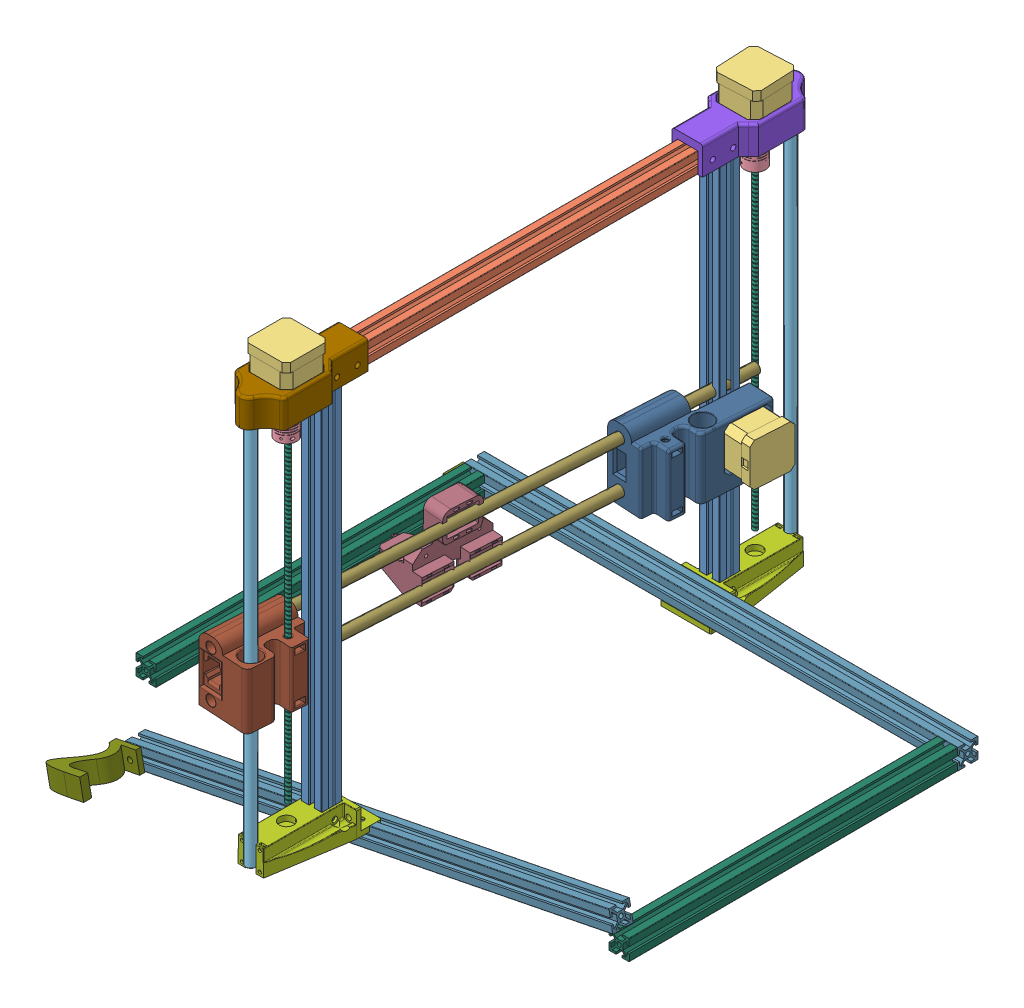
SolidWorks assembly sE1X Complete Assembly, configuration Default. Lengths in mm.
Overall size (525.97 503.54 556.73).
27 component instances, 16 part files, 45 mates.
Components (placement in the parent):
- sE1X 398mm Z axis 2020 extrusion-1: sE1X 398mm Z axis 2020 extrusion [Default] at origin size (20 398 20)
- sE1X 398mm Z axis 2020 extrusion-3: sE1X 398mm Z axis 2020 extrusion [Default] at (0 0 391.25) size (20 398 20)
- 370mm X axis 2020 extrusion-4: 370mm X axis 2020 extrusion [Default] at (0 410 -38.75) x (-1 0 0) z (0 1 0) size (20 371.25 20)
- nema17-1: nema17 [Défaut] at (0.3968 404.3307 426.15) x (1 0 0) z (0 1 0) size (42 42 71)
- nema17-2: nema17 [Défaut] at (-0.1 404.8 -35) x (0.998806 0 -0.048861) z (0 1 0) size (42 42 71)
- 5mm coupler-1: 5mm coupler [Valor predeterminado] at (-0.1 383.0903 -35) x (0 -1 0) z (-0.000286 0 1) size (25 20.35 21.4)
- 5mm coupler-2: 5mm coupler [Valor predeterminado] at (0.3968 382.7752 426.15) x (0 1 0) z (0.001793 0 0.999998) size (25 20.35 21.4)
- sE1X 398mm 10mm smooth rod-1: sE1X 398mm 10mm smooth rod [Default] at (0.2968 22.246 461.05) x (-0.139408 0 0.990235) z (0 1 0) size (10 10 390)
- sE1X 398mm 10mm smooth rod-2: sE1X 398mm 10mm smooth rod [Default] at (-0.1 409.8 -70) x (0.998806 0 -0.048861) z (0 -1 0) size (10 10 390)
- 5mm threaded rod-1: 5mm threaded rod [Default] at (2.3166 59.2307 426.4289) x (0.999998 0 -0.001793) z (0.001793 0 0.999998) size (5.07 324.29 5)
- 5mm threaded rod-2: 5mm threaded rod [Default] at (-0.1 59.7 -35) x (0.998806 0 -0.048861) z (0.048861 0 0.998806) size (5.07 324.29 5)
- sE1X Z Axis bottom bracket-2: sE1X Z Axis bottom bracket [Default] at (-0.1 29.25 33.6) x (-1 0 0) z (0 0 -1) size (50 25 103.66)
- sE1X Z Axis top motor bracket(mirrored)-1: sE1X Z Axis top motor bracket(mirrored) [Mirrored] at (-0.2968 399.8 96.45) size (50 27.84 222.86)
- sE1X Z Axis top motor bracket-3: sE1X Z Axis top motor bracket [Default] at (0.2968 399.8 426.05) size (50 27.84 111.43)
- sE1X X Axis Motor end-1: sE1X X Axis Motor end [Default] at (12.2933 178.2909 40.7975) x (0.058241 0 -0.998303) z (0.998303 0 0.058241) size (110 70.43 50)
- sE1X X idler end-1: sE1X X idler end [Default] at (-35.9747 178.2909 438.8999) x (0.058241 0 -0.998303) z (0.998303 0 0.058241) size (70 65 50)
- sE1X 465mm 10mm smooth rod-3: sE1X 465mm 10mm smooth rod [Default] at (3.9817 155.7909 -31.3582) x (0.998303 0 0.058241) z (-0.058241 0 0.998303) size (10 10 465)
- sE1X 465mm 10mm smooth rod-4: sE1X 465mm 10mm smooth rod [Default] at (4.015 200.7909 -31.9301) x (0.998303 0 0.058241) z (-0.058241 0 0.998303) size (10 10 465)
- SE1X 10mm carriage(BOWDEN)-1: SE1X 10mm carriage(BOWDEN) [10mm config] at (-21.3067 183.1903 239.5265) x (-0.058241 0 0.998303) z (-0.019423 -0.999811 -0.001133) size (75 52.26 71.73)
- nema17-3: nema17 [Défaut] at (17.6074 178.2909 9.8044) x (0.058241 0 -0.998303) z (0.998303 0 0.058241) size (42 42 71)
- sE1X 485mm Z axis 2020 extrusion-1: sE1X 485mm Z axis 2020 extrusion [Default] at (198.7408 46.1901 359.3185) x (0 0 -1) z (-0.195264 0.980751 0) size (20 485 20)
- sE1X 485mm Z axis 2020 extrusion-2: sE1X 485mm Z axis 2020 extrusion [Default] at (202.5107 31.65 23.5) x (0 1 0) z (0 0 1) size (20 485 20)
- 320mm X axis 2020 extrusion-1: 320mm X axis 2020 extrusion [Default] at (-207.4893 31.65 -63.68) x (-1 0 0) z (0 1 0) size (20 322.82 20)
- 320mm X axis 2020 extrusion-2: 320mm X axis 2020 extrusion [Default] at (257.5107 30.3656 453.4889) x (-1 0 0) z (0 -0.999995 -0.003058) size (20 322.82 20)
- Printer Supports -sE1X-1: Printer Supports -sE1X [Default] at (-228.9197 -7.5494 33) x (0 -1 0) z (1 0 0) size (55.14 20 44.55)
- Printer Supports -sE1X-2: Printer Supports -sE1X [Default] at (-214.2758 -26.3535 398.5179) x (0 0 1) z (0.980751 0.195264 0) size (55.14 20 44.55)
- sE1X Z Axis bottom bracket-3: sE1X Z Axis bottom bracket [Default] at (0.2968 29.5 357.45) size (50 25 103.66)
Mates (geometry in assembly coordinates):
- Concentric5: concentric anti-aligned: cylinder of nema17-2 through (-0.1 380.8 -35) axis (0 1 0) radius 2.5; cylinder of 5mm coupler-1 through (-0.1 370.5903 -35) axis (0 -1 0) radius 2.5
- Concentric7: concentric aligned: cylinder of nema17-1 through (0.3968 380.3307 425.9) axis (0 1 0) radius 2.5; cylinder of 5mm coupler-2 through (0.3968 395.2752 425.9) axis (0 1 0) radius 2.5
- Coincident38: coincident anti-aligned: plane of nema17-2 through (-0.1 380.8 -35) normal (0 -1 0); plane of 5mm threaded rod-2 through (-0.1 380.8 -35) normal (0 1 0)
- Concentric16: concentric aligned: cylinder of 5mm coupler-1 through (-0.1 370.5903 -35) axis (0 -1 0) radius 2.5; cylinder of 5mm threaded rod-2 through (-0.1 380.8 -35) axis (0 -1 0) radius 2.5
- Coincident39: coincident anti-aligned: plane of nema17-1 through (0.3968 380.3307 425.9) normal (0 -1 0); plane of 5mm threaded rod-1 through (2.3166 380.3307 426.1789) normal (0 1 0)
- Coincident64: coincident aligned: plane of sE1X 398mm Z axis 2020 extrusion-1 through (10 22 9.5) normal (1 0 0); plane of 370mm X axis 2020 extrusion-4 through (10 400.5 9.75) normal (1 0 0)
- Coincident65: coincident aligned: plane of sE1X 398mm Z axis 2020 extrusion-1 through (9.5 420 -9.5) normal (0 1 0); plane of 370mm X axis 2020 extrusion-4 through (9.5 420 9.75) normal (0 1 0)
- Coincident71: coincident anti-aligned: plane of sE1X 398mm Z axis 2020 extrusion-3 through (-3 22 381) normal (0 0 -1); plane of 370mm X axis 2020 extrusion-4 through (-9.5 400.5 381) normal (0 0 1)
- Coincident72: coincident anti-aligned: plane of sE1X 398mm Z axis 2020 extrusion-1 through (-9.5 22 10) normal (0 0 1); plane of 370mm X axis 2020 extrusion-4 through (-9.5 400.5 9.75) normal (0 0 -1)
- Coincident76: coincident anti-aligned: line of sE1X 398mm Z axis 2020 extrusion-1 through (3 22 10) axis (1 0 0); line of sE1X Z Axis bottom bracket-2 through (9.75 22 10) axis (-1 0 0)
- Coincident77: coincident anti-aligned: plane of sE1X 398mm Z axis 2020 extrusion-1 through (10 22 9.5) normal (1 0 0); plane of sE1X Z Axis bottom bracket-2 through (10 21.75 10) normal (-1 0 0)
- Coincident89: coincident anti-aligned: line of sE1X 398mm Z axis 2020 extrusion-3 through (3 420 401) axis (1 0 0); line of sE1X Z Axis top motor bracket-3 through (10.5936 420 401) axis (-1 0 0)
- Coincident90: coincident anti-aligned: line of sE1X 398mm Z axis 2020 extrusion-3 through (-10 420 394) axis (0 0 1); line of sE1X Z Axis top motor bracket-3 through (-10 420 401) axis (0 0 -1)
- Lock4: lock: unknown of 370mm X axis 2020 extrusion-4; unknown of sE1X Z Axis top motor bracket(mirrored)-1
- Lock5: lock: unknown of 370mm X axis 2020 extrusion-4; unknown of sE1X Z Axis top motor bracket-3
- Coincident94: coincident anti-aligned: plane of nema17-1 through (-14.4032 442.3307 446.9) normal (0 0 1); plane of sE1X Z Axis top motor bracket-3 through (-20.8032 404.8 446.9) normal (0 0 -1)
- Coincident96: coincident anti-aligned: plane of nema17-1 through (21.3968 442.3307 411.1) normal (1 0 0); plane of sE1X Z Axis top motor bracket-3 through (21.3968 404.8 446.9) normal (-1 0 0)
- Concentric27: concentric aligned: cylinder of sE1X 398mm 10mm smooth rod-1 through (0.2968 412.246 460.8) axis (0 -1 0) radius 5; cylinder of sE1X Z Axis top motor bracket-3 through (0.2968 409.8 460.8) axis (0 -1 0) radius 5.05
- Concentric32: concentric anti-aligned: cylinder of sE1X 398mm 10mm smooth rod-1 through (0.2968 412.246 460.8) axis (0 -1 0) radius 5; cylinder of sE1X X idler end-1 through (0.2968 145.7909 460.8) axis (0 1 0) radius 9.55
- Concentric33: concentric anti-aligned: cylinder of sE1X X Axis Motor end-1 through (-1.656 155.7909 65.0262) axis (-0.058241 0 0.998303) radius 5.05; cylinder of sE1X 465mm 10mm smooth rod-3 through (-23.1152 155.7909 432.8516) axis (0.058241 0 -0.998303) radius 5
- Concentric34: concentric anti-aligned: cylinder of sE1X X Axis Motor end-1 through (-1.656 200.7909 65.0262) axis (-0.058241 0 0.998303) radius 5.05; cylinder of sE1X 465mm 10mm smooth rod-4 through (-23.0818 200.7909 432.2798) axis (0.058241 0 -0.998303) radius 5
- Concentric35: concentric aligned: cylinder of sE1X X idler end-1 through (-25.5344 200.7909 474.3185) axis (0.058241 0 -0.998303) radius 5.05; cylinder of sE1X 465mm 10mm smooth rod-4 through (-23.0818 200.7909 432.2798) axis (0.058241 0 -0.998303) radius 5
- Concentric36: concentric anti-aligned: circle of sE1X X idler end-1; cylinder of sE1X 465mm 10mm smooth rod-3 through (-23.1152 155.7909 432.8516) axis (0.058241 0 -0.998303) radius 5
- Concentric40: concentric aligned: cylinder of sE1X 465mm 10mm smooth rod-3 through (-23.1152 155.7909 432.8516) axis (0.058241 0 -0.998303) radius 5; circle of SE1X 10mm carriage(BOWDEN)-1
- Coincident97: coincident anti-aligned: plane of sE1X X Axis Motor end-1 through (15.7728 178.2909 41.0005) normal (0.998303 0 0.058241); plane of nema17-3 through (17.5929 178.2909 9.8035) normal (-0.998303 0 -0.058241)
- Concentric41: concentric aligned: circle of sE1X X Axis Motor end-1; circle of nema17-3
- Parallel7: parallel anti-aligned: plane of sE1X X Axis Motor end-1 through (16.3552 157.0409 31.0175) normal (0.058241 0 -0.998303); plane of nema17-3 through (54.3053 193.0909 32.9811) normal (-0.058241 0 0.998303)
- Coincident106: coincident anti-aligned: plane of sE1X Z Axis bottom bracket-2 through (24.9 41.75 13.5) normal (0 0 1); plane of sE1X 485mm Z axis 2020 extrusion-2 through (267.5107 41.15 13.5) normal (0 0 -1)
- Coincident107: coincident anti-aligned: plane of sE1X Z Axis bottom bracket-2 through (24.9 21.65 33.6) normal (0 1 0); plane of sE1X 485mm Z axis 2020 extrusion-2 through (267.5107 21.65 14) normal (0 -1 0)
- Coincident111: coincident anti-aligned: plane of sE1X 485mm Z axis 2020 extrusion-2 through (267.5107 34.65 33.5) normal (0 0 1); plane of 320mm X axis 2020 extrusion-1 through (-216.9893 22.15 33.5) normal (0 0 -1)
- Parallel8: parallel aligned: cylinder of sE1X 485mm Z axis 2020 extrusion-2 through (267.5107 41.15 33) axis (-1 0 0) radius 0.5; line of 320mm X axis 2020 extrusion-1 through (-197.9893 41.65 33.5) axis (-1 0 0)
- Parallel10: parallel anti-aligned: cylinder of sE1X 485mm Z axis 2020 extrusion-2 through (267.5107 22.15 33) axis (-1 0 0) radius 0.5; line of 320mm X axis 2020 extrusion-1 through (-216.9893 21.65 33.5) axis (1 0 0)
- Coincident144: coincident anti-aligned: line of sE1X 485mm Z axis 2020 extrusion-2 through (-217.4893 34.65 33.5) axis (0 1 0); line of 320mm X axis 2020 extrusion-1 through (-217.4893 41.15 33.5) axis (0 -1 0)
- Coincident147: coincident aligned: plane of sE1X 485mm Z axis 2020 extrusion-2 through (267.5107 21.65 26.5) normal (0 -1 0); plane of 320mm X axis 2020 extrusion-1 through (-216.9893 21.65 33.5) normal (0 -1 0)
- Coincident188: coincident anti-aligned: plane of sE1X 485mm Z axis 2020 extrusion-2 through (267.5107 21.65 14) normal (0 -1 0); plane of Printer Supports -sE1X-1 through (-224.0949 21.65 13) normal (0 1 0)
- Coincident189: coincident anti-aligned: plane of sE1X 485mm Z axis 2020 extrusion-2 through (267.5107 21.65 20.5) normal (0 0 1); plane of Printer Supports -sE1X-1 through (-235.4182 22.15 20.5) normal (0 0 -1)
- Coincident190: coincident anti-aligned: plane of sE1X 485mm Z axis 2020 extrusion-1 through (264.3446 49.5652 369.3185) normal (0 0 1); plane of Printer Supports -sE1X-2 through (-205.6387 -45.0265 369.3185) normal (0 0 -1)
- Coincident191: coincident anti-aligned: plane of sE1X 485mm Z axis 2020 extrusion-1 through (263.0754 55.94 369.3185) normal (-0.195264 0.980751 0); plane of Printer Supports -sE1X-2 through (-218.2084 -39.8819 368.8185) normal (0.195264 -0.980751 0)
- Coincident206: coincident: line of sE1X 485mm Z axis 2020 extrusion-1 through (264.4422 49.0748 356.3185) axis (-0.195264 0.980751 0); point of 320mm X axis 2020 extrusion-2
- Coincident207: coincident: point of sE1X 485mm Z axis 2020 extrusion-2; point of 320mm X axis 2020 extrusion-2
- Parallel43: parallel anti-aligned: line of sE1X 485mm Z axis 2020 extrusion-2 through (267.5107 41.15 33.5) axis (-1 0 0); line of 320mm X axis 2020 extrusion-2 through (248.0107 41.65 33.5214) axis (1 0 0)
- Concentric51: concentric aligned: cylinder of sE1X 398mm 10mm smooth rod-2 through (-0.1 19.8 -70) axis (0 1 0) radius 5; cylinder of sE1X Z Axis bottom bracket-2 through (-0.1 16.7499 -70) axis (0 1 0) radius 5.05
- Concentric52: concentric anti-aligned: cylinder of sE1X 398mm 10mm smooth rod-1 through (0.2968 412.246 460.8) axis (0 -1 0) radius 5; cylinder of sE1X Z Axis bottom bracket-3 through (0.2968 16.9999 460.8) axis (0 1 0) radius 5.05
- Concentric53: concentric anti-aligned: cylinder of 5mm threaded rod-2 through (-0.1 380.8 -35) axis (0 -1 0) radius 2.5; cylinder of sE1X Z Axis bottom bracket-2 through (-0.1 36.25 -35) axis (0 1 0) radius 7.05
- Concentric64: concentric anti-aligned: cylinder of 5mm threaded rod-1 through (2.3166 380.3307 426.1789) axis (0 -1 0) radius 2.5; cylinder of sE1X X idler end-1 through (2.3166 145.7909 426.1789) axis (0 1 0) radius 2.75
